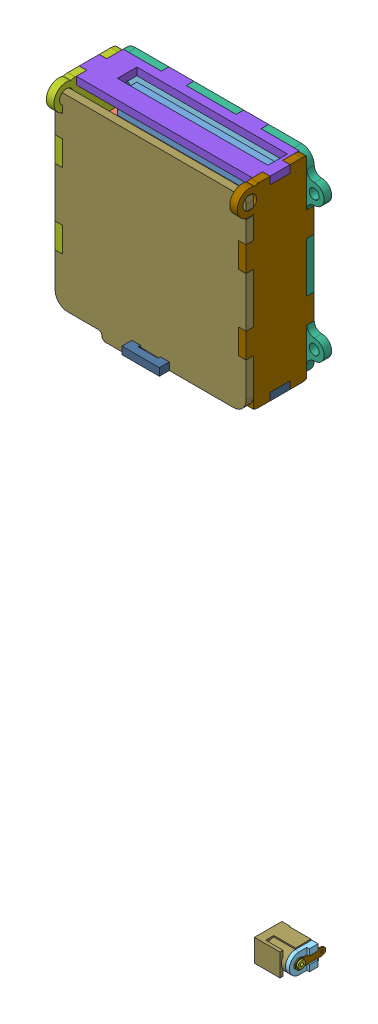
SolidWorks assembly Assem64, configuration Default. Lengths in mm.
Overall size (298.45 81 224.4).
201 component instances, 67 part files, 28 mates.
Components (placement in the parent):
- wifi_switch.STEP-1: wifi_switch.STEP [Default] at (-14.3903 37.2503 -106.003) size (288.45 72 221.81)
  - 8PIN_TERMINAL.STEP-1: 8PIN_TERMINAL.STEP [Default] at (-41 33.5 0.803) size (60.33 7.62 11.71)
    - Open CASCADE STEP translator 6.8 1.2.1.STEP-1: Open CASCADE STEP translator 6.8 1.2.1.STEP [Default] at origin size (60.33 7.62 11.71)
      - Body_1.STEP-1: Body_1.STEP [Default] at origin size (60.33 7.62 7.8)
      - Pin_1.STEP-1: Pin_1.STEP [Default] x (0 -1 0) z (0 0 1) size (1.42 1.42 8.52)
      - Pin_2.STEP-1: Pin_2.STEP [Default] at (5.0038 5.0038 0) x (0 -1 0) z (0 0 1) size (1.42 1.42 8.52)
      - Pin_3.STEP-1: Pin_3.STEP [Default] at (10.0076 10.0076 0) x (0 -1 0) z (0 0 1) size (1.42 1.42 8.52)
      - Pin_4.STEP-1: Pin_4.STEP [Default] at (15.0114 15.0114 0) x (0 -1 0) z (0 0 1) size (1.42 1.42 8.52)
      - Pin_5.STEP-1: Pin_5.STEP [Default] at (19.9898 19.9898 0) x (0 -1 0) z (0 0 1) size (1.42 1.42 8.52)
      - Pin_6.STEP-1: Pin_6.STEP [Default] at (24.9936 24.9936 0) x (0 -1 0) z (0 0 1) size (1.42 1.42 8.52)
      - Pin_7.STEP-1: Pin_7.STEP [Default] at (29.9974 29.9974 0) x (0 -1 0) z (0 0 1) size (1.42 1.42 8.52)
      - Pin_8.STEP-1: Pin_8.STEP [Default] at (35.0012 35.0012 0) x (0 -1 0) z (0 0 1) size (1.42 1.42 8.52)
      - Pin_9.STEP-1: Pin_9.STEP [Default] at (40.005 40.005 0) x (0 -1 0) z (0 0 1) size (1.42 1.42 8.52)
      - Pin_10.STEP-1: Pin_10.STEP [Default] at (45.0088 45.0088 0) x (0 -1 0) z (0 0 1) size (1.42 1.42 8.52)
      - Pin_11.STEP-1: Pin_11.STEP [Default] at (50.0126 50.0126 0) x (0 -1 0) z (0 0 1) size (1.42 1.42 8.52)
      - Pin_12.STEP-1: Pin_12.STEP [Default] at (54.991 54.991 0) x (0 -1 0) z (0 0 1) size (1.42 1.42 8.52)
  - ESP.STEP-1: ESP.STEP [Default] at (-5.5 -10.5 0.803) size (18.25 24 2.16)
    - Open CASCADE STEP translator 6.8 1.3.1.STEP-1: Open CASCADE STEP translator 6.8 1.3.1.STEP [Default] at origin size (18.25 24 2.16)
      - Body_1-0.STEP-1: Body_1-0.STEP [Default] at origin size (16 24 1.91)
      - Pin_1-1.STEP-1: Pin_1-1.STEP [Default] at origin size (1.12 2.9 1.33)
      - Pin_2-2.STEP-1: Pin_2-2.STEP [Default] at origin size (1.12 2.9 1.33)
      - Pin_3-3.STEP-1: Pin_3-3.STEP [Default] at origin size (1.12 2.9 1.33)
      - Pin_4-4.STEP-1: Pin_4-4.STEP [Default] at origin size (1.12 2.9 1.33)
      - Pin_5-5.STEP-1: Pin_5-5.STEP [Default] at origin size (1.12 2.9 1.33)
      - Pin_6-6.STEP-1: Pin_6-6.STEP [Default] at origin size (1.12 2.9 1.33)
      - Pin_7-7.STEP-1: Pin_7-7.STEP [Default] at origin size (1.12 2.9 1.33)
      - Pin_8-8.STEP-1: Pin_8-8.STEP [Default] at origin size (1.12 2.9 1.33)
      - Pin_9-9.STEP-1: Pin_9-9.STEP [Default] at (0 -28 0) x (-1 0 0) z (0 0 1) size (1.13 2.9 1.33)
      - Pin_10-10.STEP-1: Pin_10-10.STEP [Default] at (0 -24 0) x (-1 0 0) z (0 0 1) size (1.13 2.9 1.33)
      - Pin_11-11.STEP-1: Pin_11-11.STEP [Default] at (0 -20 0) x (-1 0 0) z (0 0 1) size (1.13 2.9 1.33)
      - Pin_12-12.STEP-1: Pin_12-12.STEP [Default] at (0 -16 0) x (-1 0 0) z (0 0 1) size (1.13 2.9 1.33)
      - Pin_13.STEP-1: Pin_13.STEP [Default] at (0 -12 0) x (-1 0 0) z (0 0 1) size (1.13 2.9 1.33)
      - Pin_14.STEP-1: Pin_14.STEP [Default] at (0 -8 0) x (-1 0 0) z (0 0 1) size (1.13 2.9 1.33)
      - Pin_15.STEP-1: Pin_15.STEP [Default] at (0 -4 0) x (-1 0 0) z (0 0 1) size (1.13 2.9 1.33)
      - Pin_16.STEP-1: Pin_16.STEP [Default] x (-1 0 0) z (0 0 1) size (1.13 2.9 1.33)
  - R1_470.STEP-1: R1_470.STEP [Default] at (-36 -18 0.803) x (0 1 0) z (0 0 1) size (4.78 2.7 0.65)
    - Open CASCADE STEP translator 6.8 1.4.1.STEP-1: Open CASCADE STEP translator 6.8 1.4.1.STEP [Default] at origin size (4.78 2.7 0.65)
      - Body_1-13.STEP-1: Body_1-13.STEP [Default] at origin size (4.4 2.68 0.63)
      - Pin_1-14.STEP-1: Pin_1-14.STEP [Default] at (0.374 0 0) x (-1 0 0) z (0 0 1) size (0.45 2.7 0.65)
      - Pin_2-15.STEP-1: Pin_2-15.STEP [Default] at origin size (0.45 2.7 0.65)
  - R3_470.STEP-1: R3_470.STEP [Default] at (2 -9.5 0.803) size (4.78 2.7 0.65)
    - Open CASCADE STEP translator 6.8 1.4.1.STEP-1: Open CASCADE STEP translator 6.8 1.4.1.STEP [Default] at origin size (4.78 2.7 0.65)
      - Body_1-13.STEP-1: Body_1-13.STEP [Default] at origin size (4.4 2.68 0.63)
      - Pin_1-14.STEP-1: Pin_1-14.STEP [Default] at (0.374 0 0) x (-1 0 0) z (0 0 1) size (0.45 2.7 0.65)
      - Pin_2-15.STEP-1: Pin_2-15.STEP [Default] at origin size (0.45 2.7 0.65)
  - R5_470.STEP-1: R5_470.STEP [Default] at (2 -13.5 0.803) size (4.78 2.7 0.65)
    - Open CASCADE STEP translator 6.8 1.4.1.STEP-1: Open CASCADE STEP translator 6.8 1.4.1.STEP [Default] at origin size (4.78 2.7 0.65)
      - Body_1-13.STEP-1: Body_1-13.STEP [Default] at origin size (4.4 2.68 0.63)
      - Pin_1-14.STEP-1: Pin_1-14.STEP [Default] at (0.374 0 0) x (-1 0 0) z (0 0 1) size (0.45 2.7 0.65)
      - Pin_2-15.STEP-1: Pin_2-15.STEP [Default] at origin size (0.45 2.7 0.65)
  - R7_470.STEP-1: R7_470.STEP [Default] at (2 -17.5 0.803) size (4.78 2.7 0.65)
    - Open CASCADE STEP translator 6.8 1.4.1.STEP-1: Open CASCADE STEP translator 6.8 1.4.1.STEP [Default] at origin size (4.78 2.7 0.65)
      - Body_1-13.STEP-1: Body_1-13.STEP [Default] at origin size (4.4 2.68 0.63)
      - Pin_1-14.STEP-1: Pin_1-14.STEP [Default] at (0.374 0 0) x (-1 0 0) z (0 0 1) size (0.45 2.7 0.65)
      - Pin_2-15.STEP-1: Pin_2-15.STEP [Default] at origin size (0.45 2.7 0.65)
  - OP1.STEP-1: OP1.STEP [Default] at (-35.5 -11 0.803) size (5.08 7.92 7.75)
    - Open CASCADE STEP translator 6.8 1.8.1.STEP-1: Open CASCADE STEP translator 6.8 1.8.1.STEP [Default] at origin size (5.08 7.92 7.75)
      - Body_1-16.STEP-1: Body_1-16.STEP [Default] at (1.3 3.7 0) x (0 1 0) z (1 0 0) size (7.92 7.75 5.08)
  - OP2.STEP-1: OP2.STEP [Default] at (12.5 -8.5 0.803) size (5.08 7.92 7.75)
    - Open CASCADE STEP translator 6.8 1.9.1.STEP-1: Open CASCADE STEP translator 6.8 1.9.1.STEP [Default] at origin size (5.08 7.92 7.75)
      - Body_1-16.STEP-1: Body_1-16.STEP [Default] at (1.3 3.7 0) x (0 1 0) z (1 0 0) size (7.92 7.75 5.08)
  - OP3.STEP-1: OP3.STEP [Default] at (12.5 -18 0.803) size (5.08 7.92 7.75)
    - Open CASCADE STEP translator 6.8 1.10.1.STEP-1: Open CASCADE STEP translator 6.8 1.10.1.STEP [Default] at origin size (5.08 7.92 7.75)
      - Body_1-16.STEP-1: Body_1-16.STEP [Default] at (1.3 3.7 0) x (0 1 0) z (1 0 0) size (7.92 7.75 5.08)
  - OP4.STEP-1: OP4.STEP [Default] at (12.5 -28 0.803) size (5.08 7.92 7.75)
    - Open CASCADE STEP translator 6.8 1.11.1.STEP-1: Open CASCADE STEP translator 6.8 1.11.1.STEP [Default] at origin size (5.08 7.92 7.75)
      - Body_1-16.STEP-1: Body_1-16.STEP [Default] at (1.3 3.7 0) x (0 1 0) z (1 0 0) size (7.92 7.75 5.08)
  - SMPS_5V_GND.STEP-1: SMPS_5V_GND.STEP [Default] at (-43.5 -4.5 0.803) x (0 1 0) z (0 0 1) size (10.16 10.16 15.71)
    - Open CASCADE STEP translator 6.8 1.12.1.STEP-1: Open CASCADE STEP translator 6.8 1.12.1.STEP [Default] at origin size (10.16 10.16 15.71)
      - Body_1-17.STEP-1: Body_1-17.STEP [Default] at origin size (10.16 10.16 11.8)
      - Pin_1-18.STEP-1: Pin_1-18.STEP [Default] x (0 -1 0) z (0 0 1) size (1.42 1.42 10.52)
      - Pin_2-19.STEP-1: Pin_2-19.STEP [Default] at (5.08 5.08 0) x (0 -1 0) z (0 0 1) size (1.42 1.42 10.52)
  - SMPS_L_N.STEP-1: SMPS_L_N.STEP [Default] at (-43.5 -16 0.803) x (0 1 0) z (0 0 1) size (10.16 10.16 15.71)
    - Open CASCADE STEP translator 6.8 1.12.1.STEP-1: Open CASCADE STEP translator 6.8 1.12.1.STEP [Default] at origin size (10.16 10.16 15.71)
      - Body_1-17.STEP-1: Body_1-17.STEP [Default] at origin size (10.16 10.16 11.8)
      - Pin_1-18.STEP-1: Pin_1-18.STEP [Default] x (0 -1 0) z (0 0 1) size (1.42 1.42 10.52)
      - Pin_2-19.STEP-1: Pin_2-19.STEP [Default] at (5.08 5.08 0) x (0 -1 0) z (0 0 1) size (1.42 1.42 10.52)
  - RL4.STEP-1: RL4.STEP [Default] at (-31 10 0.803) x (0 1 0) z (0 0 1) size (19.8 15.8 19.1)
    - Open CASCADE STEP translator 6.8 1.14.1.STEP-1: Open CASCADE STEP translator 6.8 1.14.1.STEP [Default] at origin size (19.8 15.8 19.1)
      - Body_1-20.STEP-1: Body_1-20.STEP [Default] at (6.5 -6 0) x (1 0 0) z (0 -1 0) size (19.8 19.1 15.8)
        - 1.STEP-1: 1.STEP [Default] at origin size (19.8 19.1 15.8)
        - 2.STEP-1: 2.STEP [Default] at origin size (1 4 0.4)
  - RL1.STEP-1: RL1.STEP [Default] at (-48 10 0.803) x (0 1 0) z (0 0 1) size (19.8 15.8 19.1)
    - Open CASCADE STEP translator 6.8 1.15.1.STEP-1: Open CASCADE STEP translator 6.8 1.15.1.STEP [Default] at origin size (19.8 15.8 19.1)
      - Body_1-1.STEP-1: Body_1-1.STEP [Default] at (6.5 -6 0) x (1 0 0) z (0 -1 0) size (19.8 19.1 15.8)
        - 1.STEP-1: 1.STEP [Default] at origin size (19.8 19.1 15.8)
        - 2.STEP-1: 2.STEP [Default] at origin size (1 4 0.4)
  - RL2.STEP-1: RL2.STEP [Default] at (-14 10 0.803) x (0 1 0) z (0 0 1) size (19.8 15.8 19.1)
    - Open CASCADE STEP translator 6.8 1.16.1.STEP-1: Open CASCADE STEP translator 6.8 1.16.1.STEP [Default] at origin size (19.8 15.8 19.1)
      - Body_1-2.STEP-1: Body_1-2.STEP [Default] at (6.5 -6 0) x (1 0 0) z (0 -1 0) size (19.8 19.1 15.8)
        - 1.STEP-1: 1.STEP [Default] at origin size (19.8 19.1 15.8)
        - 2.STEP-1: 2.STEP [Default] at origin size (1 4 0.4)
  - RL3.STEP-1: RL3.STEP [Default] at (3 10 0.803) x (0 1 0) z (0 0 1) size (19.8 15.8 19.1)
    - Open CASCADE STEP translator 6.8 1.17.1.STEP-1: Open CASCADE STEP translator 6.8 1.17.1.STEP [Default] at origin size (19.8 15.8 19.1)
      - Body_1-3.STEP-1: Body_1-3.STEP [Default] at (6.5 -6 0) x (1 0 0) z (0 -1 0) size (19.8 19.1 15.8)
        - 1.STEP-1: 1.STEP [Default] at origin size (19.8 19.1 15.8)
        - 2.STEP-1: 2.STEP [Default] at origin size (1 4 0.4)
  - DISPLAY_CONNECTOR.STEP-1: DISPLAY_CONNECTOR.STEP [Default] at (0 0 0.803) size (10.16 2.54 7.37)
    - Open CASCADE STEP translator 6.8 1.18.1.STEP-1: Open CASCADE STEP translator 6.8 1.18.1.STEP [Default] at origin size (10.16 2.54 7.37)
      - Body_1-21.STEP-1: Body_1-21.STEP [Default] at (3.8 0 0) x (1 0 0) z (0 -1 0) size (10.16 7.37 2.54)
  - DC_JACK.STEP-1: DC_JACK.STEP [Default] at (-42 -24.5 0.803) x (0 -1 0) z (0 0 1) size (9.5 14.51 14.4)
    - Open CASCADE STEP translator 6.8 1.19.1.STEP-1: Open CASCADE STEP translator 6.8 1.19.1.STEP [Default] at origin size (9.5 14.51 14.4)
      - Body_1-4.STEP-1: Body_1-4.STEP [Default] at (-1.97 277.95 212.6) x (-1 0 0) z (0 1 0) size (9.5 14.4 14.51)
        - =_[0_1_1_3].STEP-1: =_[0_1_1_3].STEP [Default] at origin size (8 10.5 2.55)
        - =_[0_1_1_4].STEP-1: =_[0_1_1_4].STEP [Default] at origin size (1.93 1.93 11.95)
        - =_[0_1_1_5].STEP-1: =_[0_1_1_5].STEP [Default] at origin size (3.3 3.3 1)
        - =_[0_1_1_6].STEP-1: =_[0_1_1_6].STEP [Default] at origin size (1.5 7.4 7.5)
        - =_[0_1_1_7].STEP-1: =_[0_1_1_7].STEP [Default] at origin size (4 12 0.5)
        - =_[0_1_1_8].STEP-1: =_[0_1_1_8].STEP [Default] at origin size (3.5 3.5 0.2)
        - =_[0_1_1_9].STEP-1: =_[0_1_1_9].STEP [Default] at origin size (2.5 3.7 0.2)
        - =_[0_1_1_10].STEP-1: =_[0_1_1_10].STEP [Default] at origin size (9 11 11.96)
  - RX.STEP-1: RX.STEP [Default] at (-3.5 -5 0.803) size (5.08 2.54 7.37)
    - Open CASCADE STEP translator 6.8 1.20.1.STEP-1: Open CASCADE STEP translator 6.8 1.20.1.STEP [Default] at origin size (5.08 2.54 7.37)
      - Body_1-22.STEP-1: Body_1-22.STEP [Default] at (1.3 0 0) x (1 0 0) z (0 -1 0) size (5.08 7.37 2.54)
  - Q1.STEP-1: Q1.STEP [Default] at (-34 1 0.803) size (4.8 20.44 3.83)
    - Open CASCADE STEP translator 6.8 1.21.1.STEP-1: Open CASCADE STEP translator 6.8 1.21.1.STEP [Default] at origin size (4.8 20.44 3.83)
      - Body_1-5.STEP-1: Body_1-5.STEP [Default] at origin size (4.8 20.44 3.83)
        - =_[0_1_1_3]-23.STEP-1: =_[0_1_1_3]-23.STEP [Default] at origin size (0.48 15.53 0.43)
        - =_[0_1_1_4]-24.STEP-1: =_[0_1_1_4]-24.STEP [Default] at origin size (0.49 15.53 0.43)
        - =_[0_1_1_5]-25.STEP-1: =_[0_1_1_5]-25.STEP [Default] at origin size (0.48 15.53 0.43)
        - =_[0_1_1_6]-26.STEP-1: =_[0_1_1_6]-26.STEP [Default] at origin size (4.8 4.95 3.83)
        - =_[0_1_1_7]-27.STEP-1: =_[0_1_1_7]-27.STEP [Default] at origin size (0.7 0.7 0.05)
  - Q2.STEP-1: Q2.STEP [Default] at (-10 1 0.803) size (4.8 20.44 3.83)
    - Open CASCADE STEP translator 6.8 1.22.1.STEP-1: Open CASCADE STEP translator 6.8 1.22.1.STEP [Default] at origin size (4.8 20.44 3.83)
      - Body_1-5.STEP-1: Body_1-5.STEP [Default] at origin size (4.8 20.44 3.83)
        - =_[0_1_1_3]-23.STEP-1: =_[0_1_1_3]-23.STEP [Default] at origin size (0.48 15.53 0.43)
        - =_[0_1_1_4]-24.STEP-1: =_[0_1_1_4]-24.STEP [Default] at origin size (0.49 15.53 0.43)
        - =_[0_1_1_5]-25.STEP-1: =_[0_1_1_5]-25.STEP [Default] at origin size (0.48 15.53 0.43)
        - =_[0_1_1_6]-26.STEP-1: =_[0_1_1_6]-26.STEP [Default] at origin size (4.8 4.95 3.83)
        - =_[0_1_1_7]-27.STEP-1: =_[0_1_1_7]-27.STEP [Default] at origin size (0.7 0.7 0.05)
  - Q3.STEP-1: Q3.STEP [Default] at (-16.5 1 0.803) size (4.8 20.44 3.83)
    - Open CASCADE STEP translator 6.8 1.23.1.STEP-1: Open CASCADE STEP translator 6.8 1.23.1.STEP [Default] at origin size (4.8 20.44 3.83)
      - Body_1-5.STEP-1: Body_1-5.STEP [Default] at origin size (4.8 20.44 3.83)
        - =_[0_1_1_3]-23.STEP-1: =_[0_1_1_3]-23.STEP [Default] at origin size (0.48 15.53 0.43)
        - =_[0_1_1_4]-24.STEP-1: =_[0_1_1_4]-24.STEP [Default] at origin size (0.49 15.53 0.43)
        - =_[0_1_1_5]-25.STEP-1: =_[0_1_1_5]-25.STEP [Default] at origin size (0.48 15.53 0.43)
        - =_[0_1_1_6]-26.STEP-1: =_[0_1_1_6]-26.STEP [Default] at origin size (4.8 4.95 3.83)
        - =_[0_1_1_7]-27.STEP-1: =_[0_1_1_7]-27.STEP [Default] at origin size (0.7 0.7 0.05)
  - Q4.STEP-1: Q4.STEP [Default] at (-22.5 1 0.803) size (4.8 20.44 3.83)
    - Open CASCADE STEP translator 6.8 1.24.1.STEP-1: Open CASCADE STEP translator 6.8 1.24.1.STEP [Default] at origin size (4.8 20.44 3.83)
      - Body_1-5.STEP-1: Body_1-5.STEP [Default] at origin size (4.8 20.44 3.83)
        - =_[0_1_1_3]-23.STEP-1: =_[0_1_1_3]-23.STEP [Default] at origin size (0.48 15.53 0.43)
        - =_[0_1_1_4]-24.STEP-1: =_[0_1_1_4]-24.STEP [Default] at origin size (0.49 15.53 0.43)
        - =_[0_1_1_5]-25.STEP-1: =_[0_1_1_5]-25.STEP [Default] at origin size (0.48 15.53 0.43)
        - =_[0_1_1_6]-26.STEP-1: =_[0_1_1_6]-26.STEP [Default] at origin size (4.8 4.95 3.83)
        - =_[0_1_1_7]-27.STEP-1: =_[0_1_1_7]-27.STEP [Default] at origin size (0.7 0.7 0.05)
  - R2_120.STEP-1: R2_120.STEP [Default] at (-32 -18 0.803) x (0 1 0) z (0 0 1) size (4.78 2.7 0.65)
    - Open CASCADE STEP translator 6.8 1.4.1.STEP-1: Open CASCADE STEP translator 6.8 1.4.1.STEP [Default] at origin size (4.78 2.7 0.65)
      - Body_1-13.STEP-1: Body_1-13.STEP [Default] at origin size (4.4 2.68 0.63)
      - Pin_1-14.STEP-1: Pin_1-14.STEP [Default] at (0.374 0 0) x (-1 0 0) z (0 0 1) size (0.45 2.7 0.65)
      - Pin_2-15.STEP-1: Pin_2-15.STEP [Default] at origin size (0.45 2.7 0.65)
  - R4_120.STEP-1: R4_120.STEP [Default] at (2 -21.5 0.803) size (4.78 2.7 0.65)
    - Open CASCADE STEP translator 6.8 1.4.1.STEP-1: Open CASCADE STEP translator 6.8 1.4.1.STEP [Default] at origin size (4.78 2.7 0.65)
      - Body_1-13.STEP-1: Body_1-13.STEP [Default] at origin size (4.4 2.68 0.63)
      - Pin_1-14.STEP-1: Pin_1-14.STEP [Default] at (0.374 0 0) x (-1 0 0) z (0 0 1) size (0.45 2.7 0.65)
      - Pin_2-15.STEP-1: Pin_2-15.STEP [Default] at origin size (0.45 2.7 0.65)
  - R6_120.STEP-1: R6_120.STEP [Default] at (2 -25.5 0.803) size (4.78 2.7 0.65)
    - Open CASCADE STEP translator 6.8 1.4.1.STEP-1: Open CASCADE STEP translator 6.8 1.4.1.STEP [Default] at origin size (4.78 2.7 0.65)
      - Body_1-13.STEP-1: Body_1-13.STEP [Default] at origin size (4.4 2.68 0.63)
      - Pin_1-14.STEP-1: Pin_1-14.STEP [Default] at (0.374 0 0) x (-1 0 0) z (0 0 1) size (0.45 2.7 0.65)
      - Pin_2-15.STEP-1: Pin_2-15.STEP [Default] at origin size (0.45 2.7 0.65)
  - R8_120.STEP-1: R8_120.STEP [Default] at (2 -29.5 0.803) size (4.78 2.7 0.65)
    - Open CASCADE STEP translator 6.8 1.4.1.STEP-1: Open CASCADE STEP translator 6.8 1.4.1.STEP [Default] at origin size (4.78 2.7 0.65)
      - Body_1-13.STEP-1: Body_1-13.STEP [Default] at origin size (4.4 2.68 0.63)
      - Pin_1-14.STEP-1: Pin_1-14.STEP [Default] at (0.374 0 0) x (-1 0 0) z (0 0 1) size (0.45 2.7 0.65)
      - Pin_2-15.STEP-1: Pin_2-15.STEP [Default] at origin size (0.45 2.7 0.65)
  - PN1.STEP-1: PN1.STEP [Default] at (-28.5 1 0.803) size (3.05 1.5 2.16)
    - Open CASCADE STEP translator 6.8 1.29.1.STEP-1: Open CASCADE STEP translator 6.8 1.29.1.STEP [Default] at origin size (3.05 1.5 2.16)
      - Body_1-28.STEP-1: Body_1-28.STEP [Default] at origin size (0.4 0.8 1.91)
      - Pin_1-29.STEP-1: Pin_1-29.STEP [Default] at origin size (1.32 1.5 1.33)
      - Pin_2-30.STEP-1: Pin_2-30.STEP [Default] at (2.8 0 0) x (-1 0 0) z (0 0 1) size (1.32 1.5 1.33)
  - PN2.STEP-1: PN2.STEP [Default] at (-27.5 -3 0.803) size (3.05 1.5 2.16)
    - Open CASCADE STEP translator 6.8 1.29.1.STEP-1: Open CASCADE STEP translator 6.8 1.29.1.STEP [Default] at origin size (3.05 1.5 2.16)
      - Body_1-28.STEP-1: Body_1-28.STEP [Default] at origin size (0.4 0.8 1.91)
      - Pin_1-29.STEP-1: Pin_1-29.STEP [Default] at origin size (1.32 1.5 1.33)
      - Pin_2-30.STEP-1: Pin_2-30.STEP [Default] at (2.8 0 0) x (-1 0 0) z (0 0 1) size (1.32 1.5 1.33)
  - PN3.STEP-1: PN3.STEP [Default] at (-27.5 -7.5 0.803) size (3.05 1.5 2.16)
    - Open CASCADE STEP translator 6.8 1.29.1.STEP-1: Open CASCADE STEP translator 6.8 1.29.1.STEP [Default] at origin size (3.05 1.5 2.16)
      - Body_1-28.STEP-1: Body_1-28.STEP [Default] at origin size (0.4 0.8 1.91)
      - Pin_1-29.STEP-1: Pin_1-29.STEP [Default] at origin size (1.32 1.5 1.33)
      - Pin_2-30.STEP-1: Pin_2-30.STEP [Default] at (2.8 0 0) x (-1 0 0) z (0 0 1) size (1.32 1.5 1.33)
  - PN4.STEP-1: PN4.STEP [Default] at (5.5 -4 0.803) size (3.05 1.5 2.16)
    - Open CASCADE STEP translator 6.8 1.29.1.STEP-1: Open CASCADE STEP translator 6.8 1.29.1.STEP [Default] at origin size (3.05 1.5 2.16)
      - Body_1-28.STEP-1: Body_1-28.STEP [Default] at origin size (0.4 0.8 1.91)
      - Pin_1-29.STEP-1: Pin_1-29.STEP [Default] at origin size (1.32 1.5 1.33)
      - Pin_2-30.STEP-1: Pin_2-30.STEP [Default] at (2.8 0 0) x (-1 0 0) z (0 0 1) size (1.32 1.5 1.33)
  - PROG.STEP-1: PROG.STEP [Default] at (-28.103 -24 0.803) x (0 1 0) z (0 0 1) size (15.24 2.54 7.37)
    - Open CASCADE STEP translator 6.8 1.33.1.STEP-1: Open CASCADE STEP translator 6.8 1.33.1.STEP [Default] at origin size (15.24 2.54 7.37)
      - Body_1-31.STEP-1: Body_1-31.STEP [Default] at (6.5 0 0) x (1 0 0) z (0 -1 0) size (15.24 7.37 2.54)
  - RESET.STEP-1: RESET.STEP [Default] at (-0.5 -26.5 0.803) x (0 1 0) z (0 0 1) size (5.08 2.54 7.37)
    - Open CASCADE STEP translator 6.8 1.34.1.STEP-1: Open CASCADE STEP translator 6.8 1.34.1.STEP [Default] at origin size (5.08 2.54 7.37)
      - Body_1-22.STEP-1: Body_1-22.STEP [Default] at (1.3 0 0) x (1 0 0) z (0 -1 0) size (5.08 7.37 2.54)
  - Layer_1.STEP-1: Layer_1.STEP [Default] at origin size (70.5 72 1.61)
- bottom_plate-1: bottom_plate [Default] at (-22.3903 53.7503 -108.5) x (0 -1 0) z (0 0 -1) size (78 90.5 3)
- side_plate-1: side_plate [Default] at (-66.8903 53.7503 -108.5) x (0 -1 0) z (-1 0 0) size (78 30.87 3)
- terminal_block_plate-1: terminal_block_plate [Default] at (-22.3903 76.7503 -108.5) x (0 0 -1) z (0 1 0) size (21.81 76.5 3)
- side_plate2-1: side_plate2 [Default] at (6.6097 53.7503 -108.5) x (0 -1 0) z (-1 0 0) size (78 30.87 3)
- back_plate-1: back_plate [Default] at (-22.3903 4.7503 -87.1882) x (0 0 1) z (0 -1 0) size (31.31 73.5 3)
- top_plate-1: top_plate [Default] at (-22.3903 27.7503 -87.1882) x (0 1 0) z (0 0 1) size (78 76.5 3) (hidden)
- OLED TFT 0.96 inch 64x128 monochrome-1: OLED TFT 0.96 inch 64x128 monochrome [Default] at (-11.2403 19.0503 -89.7882) x (-1 0 0) z (0 1 0) size (27.3 12.3 27.8)
- top_plate2-1: top_plate2 [Default] at (-22.3903 27.7503 -87.1882) x (0 1 0) z (0 0 1) size (78 76.5 3)
Mates (geometry in assembly coordinates):
- InPlace1: in place: plane of ? through (-94.1181 6.3884 -114.7356) normal (0 0 -1); plane of ? through (0 0 -114.7356) normal (0 0 -1); moOrthogonalPlaneRef_w of ? through (-94.1181 6.3884 -114.7356) normal (0 0 -1); plane of ? through (0 0 -114.7356) normal (0 1 0); plane of ? through (-94.1181 6.3884 -114.7356) normal (0 0 -1); plane of ? through (0 0 -114.7356) normal (-1 0 0); plane of ? through (-22.3903 45.2503 -108.5) normal (0 0 -1); unknown of bottom_plate-1
- Coincident1: coincident aligned: plane of wifi_switch.STEP-1/RL2.STEP-1/Open CASCADE STEP translator 6.8 1.16.1.STEP-1/Body_1-2.STEP-1/1.STEP-1; plane of bottom_plate-1
- Coincident2: coincident aligned: moOrthogonalPlaneRef_w of wifi_switch.STEP-1/RL2.STEP-1/Open CASCADE STEP translator 6.8 1.16.1.STEP-1/Body_1-2.STEP-1/1.STEP-1 through (-22.3903 53.7503 -108.5) normal (-1 0 0); plane of bottom_plate-1 through (-22.3903 53.7503 -108.5) normal (-1 0 0)
- Coincident3: coincident anti-aligned: moOrthogonalPlaneRef_w of wifi_switch.STEP-1/RL2.STEP-1/Open CASCADE STEP translator 6.8 1.16.1.STEP-1/Body_1-2.STEP-1/1.STEP-1 through (-22.3903 53.7503 -108.5) normal (0 1 0); plane of bottom_plate-1 through (-22.3903 53.7503 -108.5) normal (0 -1 0)
- InPlace2: in place: plane of ? through (-139.6181 21.8884 -117.7356) normal (-1 0 0); plane of ? through (-139.6181 0 0) normal (-1 0 0); plane of ? through (-139.6181 21.8884 -117.7356) normal (-1 0 0); plane of ? through (-139.6181 0 0) normal (0 1 0); plane of ? through (-139.6181 21.8884 -117.7356) normal (-1 0 0); plane of ? through (-139.6181 0 0) normal (0 0 1); plane of bottom_plate-1 through (-66.8903 60.7503 -111.5) normal (-1 0 0); unknown of side_plate-1
- Coincident4: coincident aligned: plane of bottom_plate-1; plane of side_plate-1
- Coincident5: coincident aligned: moOrthogonalPlaneRef_w of bottom_plate-1 through (-66.8903 53.7503 -108.5) normal (0 0 1); plane of side_plate-1 through (-66.8903 53.7503 -108.5) normal (0 0 1)
- Coincident6: coincident anti-aligned: moOrthogonalPlaneRef_w of bottom_plate-1 through (-66.8903 53.7503 -108.5) normal (0 1 0); plane of side_plate-1 through (-66.8903 53.7503 -108.5) normal (0 -1 0)
- InPlace3: in place: plane of ? through (-93.3681 37.8884 -117.7356) normal (0 1 0); plane of ? through (0 37.8884 0) normal (0 1 0); plane of ? through (-93.3681 37.8884 -117.7356) normal (0 1 0); plane of ? through (0 37.8884 0) normal (0 0 -1); plane of ? through (-93.3681 37.8884 -117.7356) normal (0 1 0); plane of ? through (0 37.8884 0) normal (1 0 0); plane of bottom_plate-1 through (-21.6403 76.7503 -111.5) normal (0 1 0); unknown of terminal_block_plate-1
- Coincident5: coincident aligned: plane of bottom_plate-1; plane of terminal_block_plate-1
- Coincident6: coincident aligned: moOrthogonalPlaneRef_w of bottom_plate-1 through (-22.3903 76.7503 -108.5) normal (-1 0 0); plane of terminal_block_plate-1 through (-22.3903 76.7503 -108.5) normal (-1 0 0)
- Coincident7: coincident anti-aligned: moOrthogonalPlaneRef_w of bottom_plate-1 through (-22.3903 76.7503 -108.5) normal (0 0 1); plane of terminal_block_plate-1 through (-22.3903 76.7503 -108.5) normal (0 0 -1)
- Coincident1: coincident anti-aligned: plane of bottom_plate-1 through (3.6097 20.7503 -111.5) normal (1 0 0); plane of side_plate2-1 through (3.6097 6.7503 -89.1882) normal (-1 0 0)
- Coincident2: coincident aligned: plane of bottom_plate-1 through (-64.8903 74.7503 -111.5) normal (0 0 -1); plane of side_plate2-1 through (3.6097 60.7503 -111.5) normal (0 0 -1)
- Coincident3: coincident anti-aligned: plane of bottom_plate-1 through (6.6097 60.7503 -111.5) normal (0 -1 0); plane of side_plate2-1 through (3.6097 60.7503 -108.5) normal (0 1 0)
- Coincident4: coincident aligned: plane of bottom_plate-1 through (-64.8903 74.7503 -111.5) normal (0 0 -1); plane of back_plate-1 through (-11.6403 1.7503 -111.5) normal (0 0 -1)
- Coincident5: coincident aligned: plane of bottom_plate-1 through (1.6097 1.7503 -111.5) normal (0 -1 0); plane of back_plate-1 through (-22.3903 1.7503 -87.1882) normal (0 -1 0)
- Coincident6: coincident anti-aligned: plane of side_plate2-1 through (3.6097 6.7503 -89.1882) normal (-1 0 0); plane of back_plate-1 through (3.6097 1.7503 -87.1882) normal (1 0 0)
- Coincident10: coincident aligned: plane of back_plate-1 through (-22.3903 1.7503 -87.1882) normal (0 -1 0); plane of top_plate-1 through (-64.8903 1.7503 -84.1882) normal (0 -1 0)
- Coincident11: coincident aligned: plane of side_plate2-1 through (6.6097 6.7503 -89.1882) normal (1 0 0); plane of top_plate-1 through (6.6097 6.7503 -84.1882) normal (1 0 0)
- Coincident12: coincident aligned: plane of side_plate2-1 through (3.6097 30.7503 -84.1882) normal (0 0 1); plane of top_plate-1 through (-64.8903 6.7503 -84.1882) normal (0 0 1)
- Parallel1: parallel aligned: plane of side_plate2-1 through (6.6097 6.7503 -89.1882) normal (1 0 0); plane of OLED TFT 0.96 inch 64x128 monochrome-1 through (2.4097 46.8503 -88.5882) normal (1 0 0)
- Distance1: distance = 4.2 mm aligned: plane of OLED TFT 0.96 inch 64x128 monochrome-1 through (2.4097 46.8503 -88.5882) normal (1 0 0); plane of side_plate2-1 through (6.6097 6.7503 -89.1882) normal (1 0 0)
- Distance2: distance = 17.3 mm aligned: plane of OLED TFT 0.96 inch 64x128 monochrome-1 through (2.4097 19.0503 -88.5882) normal (0 -1 0); plane of top_plate-1 through (-64.8903 1.7503 -84.1882) normal (0 -1 0)
- Coincident16: coincident anti-aligned: plane of top_plate-1 through (-64.8903 6.7503 -87.1882) normal (0 0 -1); plane of OLED TFT 0.96 inch 64x128 monochrome-1 through (-11.2403 19.0503 -87.1882) normal (0 0 1)
- Coincident17: coincident aligned: plane of side_plate-1 through (-69.8903 6.7503 -89.1882) normal (-1 0 0); plane of top_plate2-1 through (-69.8903 74.7503 -84.1882) normal (-1 0 0)
- Coincident18: coincident aligned: plane of side_plate-1 through (-69.8903 60.7503 -84.1882) normal (0 0 1); plane of top_plate2-1 through (-64.8903 6.7503 -84.1882) normal (0 0 1)
- Coincident19: coincident aligned: plane of back_plate-1 through (-22.3903 1.7503 -87.1882) normal (0 -1 0); plane of top_plate2-1 through (-64.8903 1.7503 -84.1882) normal (0 -1 0)
